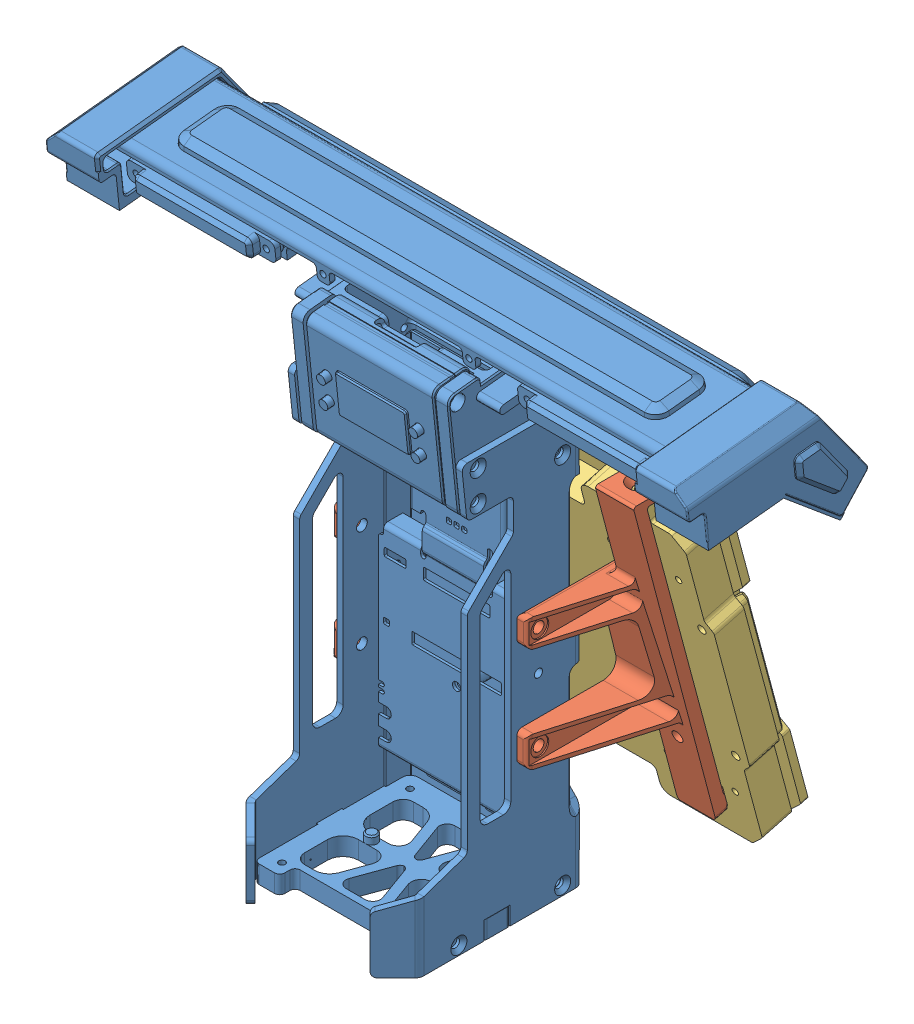
SolidWorks assembly 装配体5, configuration 默认. Lengths in mm.
Overall size (254.6 207.47 130.58).
3 component instances, 3 part files, 6 mates.
Components (placement in the parent):
- 主控模块-1: 主控模块 [默认] at (-39.7297 -102.7138 268.6542) size (254.6 207.47 93.71)
- 装甲支撑架（A）-1: 装甲支撑架（A） [默认] at (-39.7297 -102.7138 268.6542) size (110 123.07 65.99)
- 小装甲-1: 小装甲 [默认] at (-39.7297 -102.7138 268.6542) size (141 126.74 52.99)
Mates (geometry in assembly coordinates):
- 重合1: coincident: plane of 主控模块-1 through (-5.7297 62.2862 227.4542) normal (1 0 0); plane of 装甲支撑架（A）-1 through (-5.7297 1.9728 267.7781) normal (-1 0 0)
- 同心1: concentric: cylinder of 主控模块-1 through (-15.7297 -3.7138 248.9199) axis (1 0 0) radius 2.1; cylinder of 装甲支撑架（A）-1 through (-10.4797 -3.7138 248.9199) axis (1 0 0) radius 2.1
- 同心2: concentric aligned: cylinder of 主控模块-1 through (-15.7297 -43.7138 248.9199) axis (1 0 0) radius 2.1; cylinder of 装甲支撑架（A）-1 through (-10.4797 -43.7138 248.9199) axis (1 0 0) radius 2.1
- 重合2: coincident: plane of 装甲支撑架（A）-1 through (7.7703 23.5974 221.5989) normal (0 0.258819 -0.965926); plane of 小装甲-1 through (-39.7297 -33.1617 206.3903) normal (0 -0.258819 0.965926)
- 重合3: coincident: plane of 装甲支撑架（A）-1 through (15.2703 -85.2431 192.9528) normal (1 0 0); plane of 小装甲-1 through (15.2703 -33.1617 206.3903) normal (1 0 0)
- 重合4: coincident anti-aligned: plane of 装甲支撑架（A）-1 through (0.2703 33.2123 213.3048) normal (0 -1 0); plane of 小装甲-1 through (0.2703 33.2123 224.1752) normal (0 1 0)
